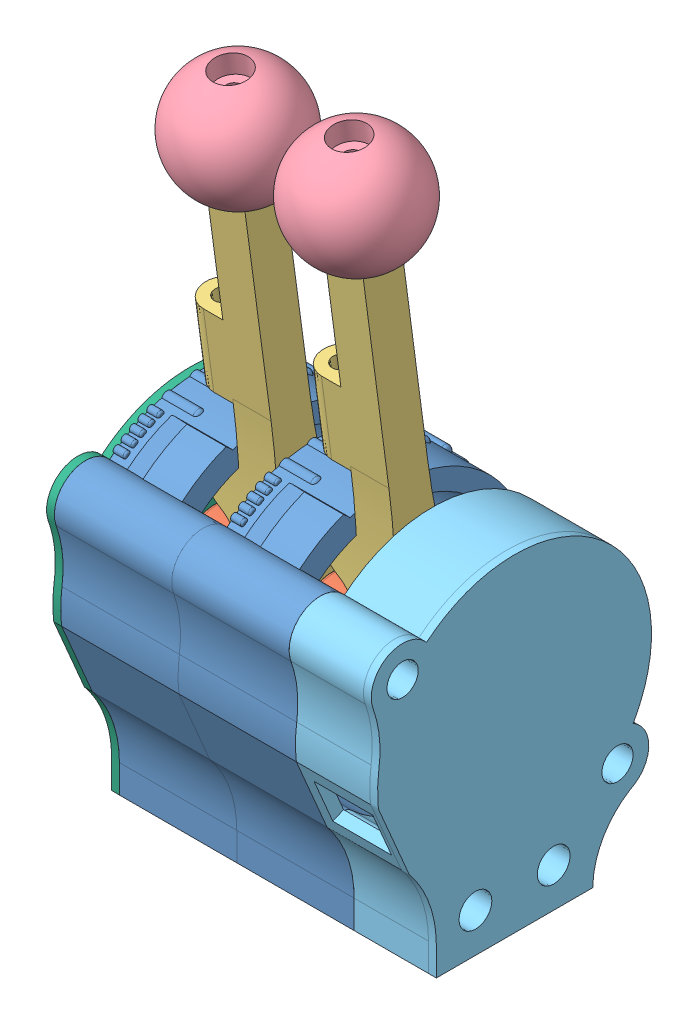
SolidWorks assembly hq, configuration По умолчанию. Lengths in mm.
Overall size (83.15 173.6 92.61).
10 component instances, 6 part files, 23 mates.
Components (placement in the parent):
- hq_pot_frame_hq01-1: hq_pot_frame_hq01 [По умолчанию] at (37.948 51.1849 72.0068) x (0 0 -1) z (0 -1 0) size (73.09 39.5 84.38)
- hq_pot_frame_hq01-2: hq_pot_frame_hq01 [По умолчанию] at (7.948 51.1849 72.0068) x (0 0 -1) z (0 -1 0) size (73.09 39.5 84.38)
- 16K1-B10K-1: 16K1-B10K [По умолчанию] at (12.048 51.1849 72.0068) x (0 -1 0) z (0 0 1) size (20 28.16 16.3)
- 16K1-B10K-2: 16K1-B10K [По умолчанию] at (42.048 51.1849 72.0068) x (0 -1 0) z (0 0 1) size (20 28.16 16.3)
- hq_lever_base_hq02-1: hq_lever_base_hq02 [По умолчанию] at (27.948 51.1849 72.0068) x (1 0 0) z (0 -0.133344 0.99107) size (19.8 118.66 20)
- hq_lever_base_hq02-2: hq_lever_base_hq02 [По умолчанию] at (57.948 51.1849 72.0068) x (1 0 0) z (0 -0.130744 0.991416) size (19.8 118.66 20)
- hq_cap_sperical_hq07-1: hq_cap_sperical_hq07 [По умолчанию] at (32.848 159.6482 86.6001) x (0 0.133344 -0.99107) z (0 -0.99107 -0.133344) size (30 30 25.49)
- hq_side_cover_right_socketed_hq05-1: hq_side_cover_right_socketed_hq05 [По умолчанию] at (61.948 51.1849 72.0068) x (0 0 -1) z (0 -1 0) size (92.61 21 108.6)
- hq_pot_side_cover_left_hq04-5: hq_pot_side_cover_left_hq04 [По умолчанию] at (-6.052 51.1849 72.0068) x (0 0 -1) z (0 -1 0) size (92.61 11.65 108.52)
- hq_cap_sperical_hq07-2: hq_cap_sperical_hq07 [По умолчанию] at (62.848 159.6861 86.3155) x (1 0 0) z (0 -0.991416 -0.130744) size (30 30 25.49)
Mates (geometry in assembly coordinates):
- Concentric1: concentric aligned: cylinder of hq_pot_frame_hq01-1 through (37.948 12.4621 82.0068) axis (1 0 0) radius 4.2; cylinder of hq_pot_frame_hq01-2 through (7.948 12.4621 82.0068) axis (1 0 0) radius 4.2
- Concentric2: concentric aligned: cylinder of hq_pot_frame_hq01-1 through (37.948 12.4621 62.0068) axis (1 0 0) radius 4.2; cylinder of hq_pot_frame_hq01-2 through (7.948 12.4621 62.0068) axis (1 0 0) radius 4.2
- Coincident2: coincident anti-aligned: plane of hq_pot_frame_hq01-1 through (37.948 51.1849 72.0068) normal (-1 0 0); plane of hq_pot_frame_hq01-2 through (37.948 51.1849 72.0068) normal (1 0 0)
- Concentric3: concentric anti-aligned: cylinder of hq_pot_frame_hq01-1 through (37.948 51.1849 72.0068) axis (1 0 0) radius 3.7; cylinder of 16K1-B10K-2 through (57.348 51.1849 72.0068) axis (-1 0 0) radius 3.35
- Coincident3: coincident anti-aligned: plane of hq_pot_frame_hq01-1 through (50.948 51.1849 72.0068) normal (-1 0 0); plane of 16K1-B10K-2 through (50.948 51.1849 72.0068) normal (1 0 0)
- Concentric4: concentric anti-aligned: cylinder of hq_pot_frame_hq01-2 through (7.948 51.1849 72.0068) axis (1 0 0) radius 3.7; cylinder of 16K1-B10K-1 through (27.348 51.1849 72.0068) axis (-1 0 0) radius 3.35
- Coincident4: coincident anti-aligned: plane of hq_pot_frame_hq01-2 through (20.948 51.1849 72.0068) normal (-1 0 0); plane of 16K1-B10K-1 through (20.948 51.1849 72.0068) normal (1 0 0)
- Coincident5: coincident anti-aligned: plane of hq_pot_frame_hq01-1 through (57.948 51.1849 72.0068) normal (1 0 0); plane of hq_lever_base_hq02-2 through (57.948 51.1849 72.0068) normal (-1 0 0)
- Concentric6: concentric aligned: cylinder of 16K1-B10K-1 through (40.148 51.1849 72.0068) axis (-1 0 0) radius 2.9; cylinder of hq_lever_base_hq02-1 through (37.748 51.1849 72.0068) axis (-1 0 0) radius 3
- Coincident6: coincident anti-aligned: plane of hq_pot_frame_hq01-2 through (27.948 51.1849 72.0068) normal (1 0 0); plane of hq_lever_base_hq02-1 through (27.948 51.1849 72.0068) normal (-1 0 0)
- Concentric18: concentric anti-aligned: cylinder of hq_lever_base_hq02-1 through (32.848 129.1427 82.4957) axis (0 0.99107 0.133344) radius 2.1; cylinder of hq_cap_sperical_hq07-1 through (32.848 174.5142 88.6002) axis (0 -0.99107 -0.133344) radius 2.15
- Parallel1: parallel aligned: plane of hq_lever_base_hq02-1 through (37.748 158.2081 91.4514) normal (0 -0.133344 0.99107); plane of hq_cap_sperical_hq07-1 through (27.698 159.5615 81.392) normal (0 -0.133344 0.99107)
- Coincident17: coincident anti-aligned: plane of hq_lever_base_hq02-1 through (37.748 159.5415 81.5407) normal (0 0.99107 0.133344); plane of hq_cap_sperical_hq07-1 through (32.848 158.8748 86.496) normal (0 -0.99107 -0.133344)
- Concentric20: concentric aligned: cylinder of hq_pot_frame_hq01-1 through (37.948 12.4621 82.0068) axis (1 0 0) radius 4.2; cylinder of hq_side_cover_right_socketed_hq05-1 through (61.948 12.4621 82.0068) axis (1 0 0) radius 4.2
- Concentric21: concentric anti-aligned: cylinder of hq_pot_frame_hq01-1 through (77.448 12.4621 62.0068) axis (-1 0 0) radius 4.1; cylinder of hq_side_cover_right_socketed_hq05-1 through (61.948 12.4621 62.0068) axis (1 0 0) radius 4.2
- Coincident20: coincident anti-aligned: plane of hq_pot_frame_hq01-1 through (67.948 51.1849 72.0068) normal (1 0 0); plane of hq_side_cover_right_socketed_hq05-1 through (67.948 24.8428 118.1852) normal (-1 0 0)
- Concentric22: concentric aligned: cylinder of hq_pot_frame_hq01-2 through (7.948 12.4621 82.0068) axis (1 0 0) radius 4.2; cylinder of hq_pot_side_cover_left_hq04-5 through (-6.052 12.4621 82.0068) axis (1 0 0) radius 4.2
- Concentric23: concentric aligned: cylinder of hq_pot_frame_hq01-2 through (7.948 12.4621 62.0068) axis (1 0 0) radius 4.2; cylinder of hq_pot_side_cover_left_hq04-5 through (-6.052 12.4621 62.0068) axis (1 0 0) radius 4.2
- Coincident21: coincident anti-aligned: plane of hq_pot_frame_hq01-2 through (7.948 51.1849 72.0068) normal (-1 0 0); plane of hq_pot_side_cover_left_hq04-5 through (7.948 75.6886 47.0155) normal (1 0 0)
- Concentric24: concentric anti-aligned: cylinder of hq_lever_base_hq02-2 through (62.848 129.17 82.2912) axis (0 0.991416 0.130744) radius 2.1; cylinder of hq_cap_sperical_hq07-2 through (62.848 174.5573 88.2767) axis (0 -0.991416 -0.130744) radius 2.15
- Coincident22: coincident anti-aligned: plane of hq_lever_base_hq02-2 through (67.748 159.5662 81.2564) normal (0 0.991416 0.130744); plane of hq_cap_sperical_hq07-2 through (62.848 158.9125 86.2135) normal (0 -0.991416 -0.130744)
- Parallel2: parallel: plane of hq_lever_base_hq02-2 through (67.748 51.1849 72.0068) normal (1 0 0); line of hq_cap_sperical_hq07-2 through (57.698 149.2903 90.1392) axis (0 0.130744 -0.991416)
- Concentric25: concentric aligned: cylinder of 16K1-B10K-2 through (70.148 51.1849 72.0068) axis (-1 0 0) radius 2.9; cylinder of hq_lever_base_hq02-2 through (67.748 51.1849 72.0068) axis (-1 0 0) radius 3
